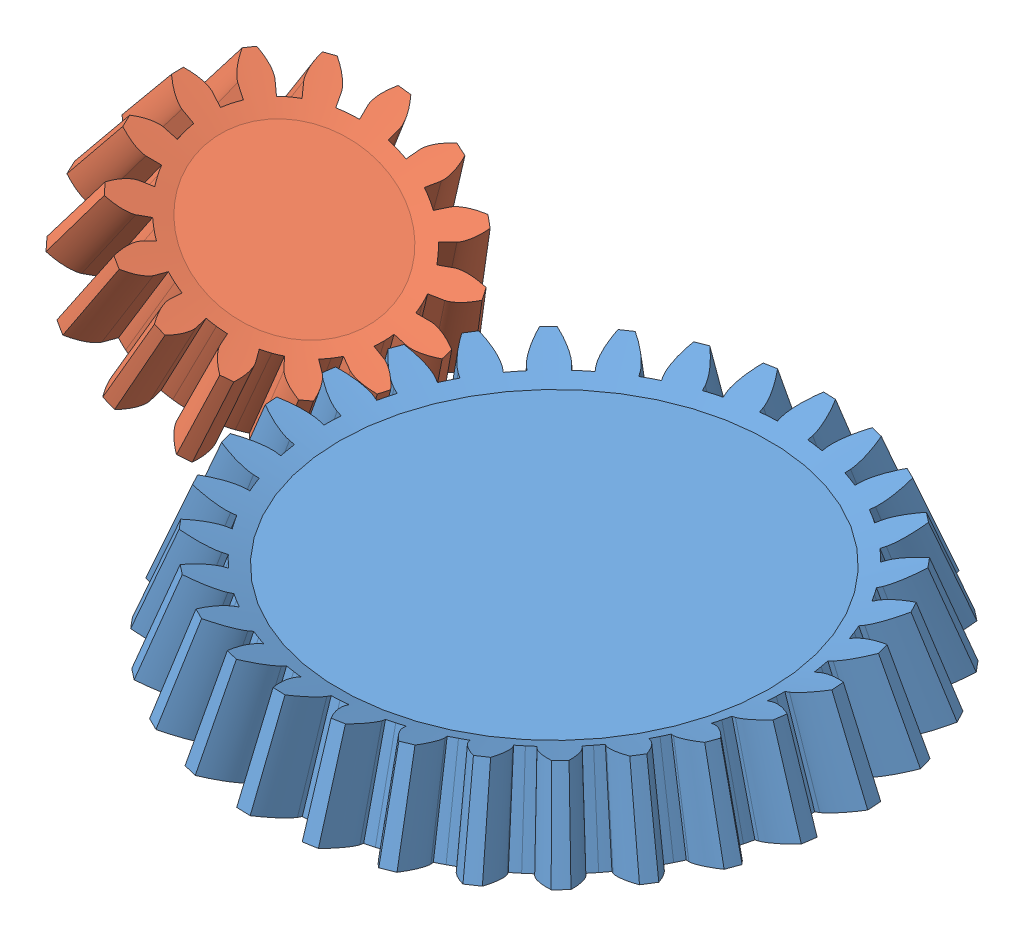
SolidWorks assembly Assem1, configuration Default. Lengths in mm.
Overall size (93.43 28.61 64.08).
2 component instances, 2 part files, 3 mates.
Components (placement in the parent):
- Main Bevel Gear-1: Main Bevel Gear [Default] at (-9.9606 30.1085 68.8056) size (63.69 11.94 63.75)
- Secondary Bevel Gear Left-1: Secondary Bevel Gear Left [Default] at (-51.5751 37.6558 58.0857) x (-0.799085 0.495754 -0.340133) z (0.356398 -0.065021 -0.932069) size (33.86 11.11 33.74)
Mates (geometry in assembly coordinates):
- Coincident3: coincident: point of Main Bevel Gear-1; point of Secondary Bevel Gear Left-1
- Angle1: planar angle = 0.523599 rad aligned: line of Secondary Bevel Gear Left-1 through (-9.9606 112.0873 68.8056) axis (-0.484193 -0.866025 -0.124728); line of Main Bevel Gear-1 through (-9.9606 112.0873 68.8056) axis (0 -1 0)
- GearMate2: gear = 30 : 60 mm: circle of Main Bevel Gear-1; circle of Secondary Bevel Gear Left-1
